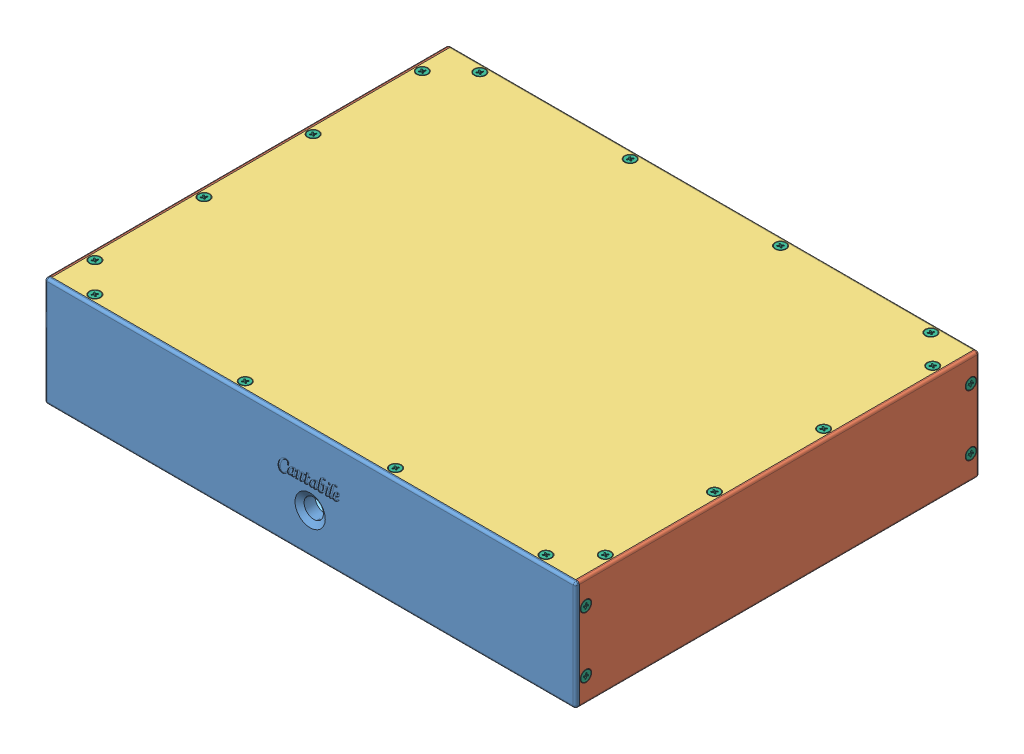
SolidWorks assembly 組合, configuration 預設. Lengths in mm.
Overall size (438 90 333).
46 component instances, 6 part files, 55 mates.
Components (placement in the parent):
- FrontPanel-2: FrontPanel [預設] at (-248.0238 109.7801 407.0399) size (438 90 12)
- SidePanel-3: SidePanel [預設] at (189.9762 199.7801 416.0399) x (0 0 -1) z (-1 0 0) size (330 90 12)
- SidePanel-4: SidePanel [預設] at (-248.0238 109.7801 416.0399) x (0 0 -1) z (1 0 0) size (330 90 12)
- top-1: top [預設] at (186.9762 195.7801 86.0399) x (-1 0 0) z (0 0 -1) size (432 4 330)
- BackPanel-2: BackPanel [預設] at (-236.0238 113.7801 86.0399) size (414 82 12)
- Bottom-1: Bottom [預設] at (186.9762 109.7801 86.0399) x (-1 0 0) z (0 0 -1) size (432 4 330)
- countersunk flat head cross recess screw_iso-1: countersunk flat head cross recess screw_iso [ISO 7046-1 - M4 x 8 - Z - 8C] at (-239.5238 199.7801 386.0399) x (0 -1 0) z (0.546944 0 -0.837169) size (8 8.4 8.4)
- countersunk flat head cross recess screw_iso-2: countersunk flat head cross recess screw_iso [ISO 7046-1 - M4 x 8 - Z - 8C] at (32.9762 199.7801 410.5399) x (0 -1 0) z (0.546944 0 -0.837169) size (8 8.4 8.4)
- countersunk flat head cross recess screw_iso-3: countersunk flat head cross recess screw_iso [ISO 7046-1 - M4 x 8 - Z - 8C] at (-215.0238 199.7801 410.5399) x (0 -1 0) z (0.546944 0 -0.837169) size (8 8.4 8.4)
- countersunk flat head cross recess screw_iso-4: countersunk flat head cross recess screw_iso [ISO 7046-1 - M4 x 8 - Z - 8C] at (-239.5238 199.7801 296.0399) x (0 -1 0) z (0.546944 0 -0.837169) size (8 8.4 8.4)
- countersunk flat head cross recess screw_iso-5: countersunk flat head cross recess screw_iso [ISO 7046-1 - M4 x 8 - Z - 8C] at (-215.0238 199.7801 93.0399) x (0 -1 0) z (0.546944 0 -0.837169) size (8 8.4 8.4)
- countersunk flat head cross recess screw_iso-6: countersunk flat head cross recess screw_iso [ISO 7046-1 - M4 x 8 - Z - 8C] at (-91.0238 199.7801 93.0399) x (0 -1 0) z (0.546944 0 -0.837169) size (8 8.4 8.4)
- countersunk flat head cross recess screw_iso-7: countersunk flat head cross recess screw_iso [ISO 7046-1 - M4 x 8 - Z - 8C] at (32.9762 199.7801 93.0399) x (0 -1 0) z (0.546944 0 -0.837169) size (8 8.4 8.4)
- countersunk flat head cross recess screw_iso-8: countersunk flat head cross recess screw_iso [ISO 7046-1 - M4 x 8 - Z - 8C] at (-91.0238 199.7801 410.5399) x (0 -1 0) z (0.546944 0 -0.837169) size (8 8.4 8.4)
- countersunk flat head cross recess screw_iso-9: countersunk flat head cross recess screw_iso [ISO 7046-1 - M4 x 8 - Z - 8C] at (-239.5238 199.7801 116.0399) x (0 -1 0) z (0.546944 0 -0.837169) size (8 8.4 8.4)
- countersunk flat head cross recess screw_iso-10: countersunk flat head cross recess screw_iso [ISO 7046-1 - M4 x 8 - Z - 8C] at (181.4762 199.7801 116.0399) x (0 -1 0) z (0.546944 0 -0.837169) size (8 8.4 8.4)
- countersunk flat head cross recess screw_iso-11: countersunk flat head cross recess screw_iso [ISO 7046-1 - M4 x 8 - Z - 8C] at (156.9762 199.7801 93.0399) x (0 -1 0) z (0.546944 0 -0.837169) size (8 8.4 8.4)
- countersunk flat head cross recess screw_iso-12: countersunk flat head cross recess screw_iso [ISO 7046-1 - M4 x 8 - Z - 8C] at (-248.0238 179.7801 410.5399) x (1 0 0) z (0 -0.564882 -0.825172) size (8 8.4 8.4)
- countersunk flat head cross recess screw_iso-13: countersunk flat head cross recess screw_iso [ISO 7046-1 - M4 x 8 - Z - 8C] at (-248.0238 179.7801 93.0399) x (1 0 0) z (0 -0.564882 -0.825172) size (8 8.4 8.4)
- countersunk flat head cross recess screw_iso-14: countersunk flat head cross recess screw_iso [ISO 7046-1 - M4 x 8 - Z - 8C] at (-248.0238 129.7801 410.5399) x (1 0 0) z (0 -0.564882 -0.825172) size (8 8.4 8.4)
- countersunk flat head cross recess screw_iso-15: countersunk flat head cross recess screw_iso [ISO 7046-1 - M4 x 8 - Z - 8C] at (181.4762 199.7801 296.0399) x (0 -1 0) z (0.546944 0 -0.837169) size (8 8.4 8.4)
- countersunk flat head cross recess screw_iso-16: countersunk flat head cross recess screw_iso [ISO 7046-1 - M4 x 8 - Z - 8C] at (181.4762 199.7801 206.0399) x (0 -1 0) z (0.546944 0 -0.837169) size (8 8.4 8.4)
- countersunk flat head cross recess screw_iso-17: countersunk flat head cross recess screw_iso [ISO 7046-1 - M4 x 8 - Z - 8C] at (156.9762 199.7801 410.5399) x (0 -1 0) z (0.546944 0 -0.837169) size (8 8.4 8.4)
- countersunk flat head cross recess screw_iso-18: countersunk flat head cross recess screw_iso [ISO 7046-1 - M4 x 8 - Z - 8C] at (181.4762 199.7801 386.0399) x (0 -1 0) z (0.546944 0 -0.837169) size (8 8.4 8.4)
- countersunk flat head cross recess screw_iso-19: countersunk flat head cross recess screw_iso [ISO 7046-1 - M4 x 8 - Z - 8C] at (-239.5238 199.7801 206.0399) x (0 -1 0) z (0.546944 0 -0.837169) size (8 8.4 8.4)
- countersunk flat head cross recess screw_iso-20: countersunk flat head cross recess screw_iso [ISO 7046-1 - M4 x 8 - Z - 8C] at (-91.0238 109.7801 93.0399) x (0 1 0) z (0 0 1) size (8 8.4 8.4)
- countersunk flat head cross recess screw_iso-21: countersunk flat head cross recess screw_iso [ISO 7046-1 - M4 x 8 - Z - 8C] at (-215.0238 109.7801 93.0399) x (0 1 0) z (0 0 1) size (8 8.4 8.4)
- countersunk flat head cross recess screw_iso-22: countersunk flat head cross recess screw_iso [ISO 7046-1 - M4 x 8 - Z - 8C] at (-239.5238 109.7801 116.0399) x (0 1 0) z (0 0 1) size (8 8.4 8.4)
- countersunk flat head cross recess screw_iso-26: countersunk flat head cross recess screw_iso [ISO 7046-1 - M4 x 8 - Z - 8C] at (-215.0238 109.7801 410.5399) x (0 1 0) z (0 0 -1) size (8 8.4 8.4)
- countersunk flat head cross recess screw_iso-27: countersunk flat head cross recess screw_iso [ISO 7046-1 - M4 x 8 - Z - 8C] at (-248.0238 129.7801 93.0399) x (1 0 0) z (0 -0.564882 -0.825172) size (8 8.4 8.4)
- countersunk flat head cross recess screw_iso-28: countersunk flat head cross recess screw_iso [ISO 7046-1 - M4 x 8 - Z - 8C] at (-239.5238 109.7801 296.0399) x (0 1 0) z (0 0 1) size (8 8.4 8.4)
- countersunk flat head cross recess screw_iso-29: countersunk flat head cross recess screw_iso [ISO 7046-1 - M4 x 8 - Z - 8C] at (-239.5238 109.7801 206.0399) x (0 1 0) z (0 0 1) size (8 8.4 8.4)
- countersunk flat head cross recess screw_iso-30: countersunk flat head cross recess screw_iso [ISO 7046-1 - M4 x 8 - Z - 8C] at (-91.0238 109.7801 410.5399) x (0 1 0) z (0 0 1) size (8 8.4 8.4)
- countersunk flat head cross recess screw_iso-31: countersunk flat head cross recess screw_iso [ISO 7046-1 - M4 x 8 - Z - 8C] at (-239.5238 109.7801 386.0399) x (0 1 0) z (0 0 1) size (8 8.4 8.4)
- countersunk flat head cross recess screw_iso-32: countersunk flat head cross recess screw_iso [ISO 7046-1 - M4 x 8 - Z - 8C] at (189.9762 129.7801 410.5399) x (-1 0 0) z (0 -0.982583 0.185827) size (8 8.4 8.4)
- countersunk flat head cross recess screw_iso-33: countersunk flat head cross recess screw_iso [ISO 7046-1 - M4 x 8 - Z - 8C] at (32.9762 109.7801 93.0399) x (0 1 0) z (0 0 1) size (8 8.4 8.4)
- countersunk flat head cross recess screw_iso-34: countersunk flat head cross recess screw_iso [ISO 7046-1 - M4 x 8 - Z - 8C] at (156.9762 109.7801 410.5399) x (0 1 0) z (0 0 1) size (8 8.4 8.4)
- countersunk flat head cross recess screw_iso-35: countersunk flat head cross recess screw_iso [ISO 7046-1 - M4 x 8 - Z - 8C] at (189.9762 179.7801 93.0399) x (-1 0 0) z (0 -0.982583 0.185827) size (8 8.4 8.4)
- countersunk flat head cross recess screw_iso-36: countersunk flat head cross recess screw_iso [ISO 7046-1 - M4 x 8 - Z - 8C] at (181.4762 109.7801 386.0399) x (0 1 0) z (0 0 1) size (8 8.4 8.4)
- countersunk flat head cross recess screw_iso-37: countersunk flat head cross recess screw_iso [ISO 7046-1 - M4 x 8 - Z - 8C] at (32.9762 109.7801 410.5399) x (0 1 0) z (0 0 1) size (8 8.4 8.4)
- countersunk flat head cross recess screw_iso-38: countersunk flat head cross recess screw_iso [ISO 7046-1 - M4 x 8 - Z - 8C] at (189.9762 129.7801 93.0399) x (-1 0 0) z (0 -0.982583 0.185827) size (8 8.4 8.4)
- countersunk flat head cross recess screw_iso-39: countersunk flat head cross recess screw_iso [ISO 7046-1 - M4 x 8 - Z - 8C] at (181.4762 109.7801 296.0399) x (0 1 0) z (0 0 1) size (8 8.4 8.4)
- countersunk flat head cross recess screw_iso-40: countersunk flat head cross recess screw_iso [ISO 7046-1 - M4 x 8 - Z - 8C] at (156.9762 109.7801 93.0399) x (0 1 0) z (0 0 1) size (8 8.4 8.4)
- countersunk flat head cross recess screw_iso-41: countersunk flat head cross recess screw_iso [ISO 7046-1 - M4 x 8 - Z - 8C] at (181.4762 109.7801 206.0399) x (0 1 0) z (0 0 1) size (8 8.4 8.4)
- countersunk flat head cross recess screw_iso-42: countersunk flat head cross recess screw_iso [ISO 7046-1 - M4 x 8 - Z - 8C] at (181.4762 109.7801 116.0399) x (0 1 0) z (0 0 1) size (8 8.4 8.4)
- countersunk flat head cross recess screw_iso-44: countersunk flat head cross recess screw_iso [ISO 7046-1 - M4 x 8 - Z - 8C] at (189.9762 179.7801 410.5399) x (-1 0 0) z (0 -0.982583 0.185827) size (8 8.4 8.4)
Mates (geometry in assembly coordinates):
- 重合/共線/共點1: coincident: plane of assembly; plane of assembly; plane of FrontPanel-2 through (-248.0238 199.7801 416.0399) normal (0 0 -1); plane of SidePanel-3 through (177.9762 199.7801 416.0399) normal (0 0 1)
- 重合/共線/共點2: coincident: line of assembly; line of assembly; line of FrontPanel-2 through (189.9762 197.7801 416.0399) axis (0 -1 0); line of SidePanel-3 through (189.9762 111.7801 416.0399) axis (0 1 0)
- 重合/共線/共點4: coincident: line of assembly; line of assembly; line of FrontPanel-2 through (-246.0238 199.7801 416.0399) axis (1 0 0); line of SidePanel-3 through (186.9762 199.7801 416.0399) axis (1 0 0)
- 重合/共線/共點6: coincident: plane of assembly; plane of assembly; plane of FrontPanel-2 through (-248.0238 199.7801 416.0399) normal (0 0 -1); plane of SidePanel-4 through (-236.0238 109.7801 416.0399) normal (0 0 1)
- 重合/共線/共點7: coincident: plane of assembly; plane of assembly; plane of FrontPanel-2 through (-236.0238 109.7801 407.0399) normal (-1 0 0); plane of SidePanel-4 through (-236.0238 109.7801 416.0399) normal (1 0 0)
- 重合/共線/共點8: coincident: line of assembly; line of assembly; line of FrontPanel-2 through (-236.0238 195.7801 416.0399) axis (0 0 -1); line of SidePanel-4 through (-236.0238 195.7801 86.0399) axis (0 0 1)
- 重合/共線/共點17: coincident: plane of assembly; plane of assembly; plane of FrontPanel-2 through (-248.0238 195.7801 407.0399) normal (0 1 0); plane of top-1 through (186.9762 195.7801 86.0399) normal (0 -1 0)
- 重合/共線/共點18: coincident: plane of assembly; plane of assembly; plane of SidePanel-4 through (-245.0238 199.7801 86.0399) normal (1 0 0); plane of top-1 through (-245.0238 199.7801 86.0399) normal (-1 0 0)
- 重合/共線/共點19: coincident: plane of assembly; plane of assembly; plane of FrontPanel-2 through (-248.0238 199.7801 416.0399) normal (0 0 -1); plane of top-1 through (186.9762 199.7801 416.0399) normal (0 0 1)
- 重合/共線/共點20: coincident: plane of assembly; plane of assembly; plane of top-1 through (186.9762 195.7801 86.0399) normal (0 -1 0); plane of BackPanel-2 through (-236.0238 195.7801 98.0399) normal (0 1 0)
- 重合/共線/共點21: coincident: line of assembly; line of assembly; line of top-1 through (186.9762 195.7801 86.0399) axis (-1 0 0); line of BackPanel-2 through (177.9762 195.7801 86.0399) axis (-1 0 0)
- 重合/共線/共點22: coincident: plane of assembly; plane of assembly; plane of SidePanel-4 through (-236.0238 109.7801 416.0399) normal (1 0 0); plane of BackPanel-2 through (-236.0238 113.7801 98.0399) normal (-1 0 0)
- 重合/共線/共點29: coincident: plane of assembly; plane of assembly; plane of BackPanel-2 through (-236.0238 113.7801 98.0399) normal (0 -1 0); plane of Bottom-1 through (186.9762 113.7801 86.0399) normal (0 1 0)
- 重合/共線/共點30: coincident: line of assembly; line of assembly; line of BackPanel-2 through (-236.0238 113.7801 86.0399) axis (1 0 0); line of Bottom-1 through (186.9762 113.7801 86.0399) axis (-1 0 0)
- 重合/共線/共點32: coincident: line of assembly; line of assembly; line of SidePanel-4 through (-245.0238 113.7801 86.0399) axis (0 0 1); line of Bottom-1 through (-245.0238 113.7801 86.0399) axis (0 0 1)
- 重合/共線/共點33: coincident: cone of assembly; cone of assembly; cone of top-1 through (-239.5238 199.7801 386.0399) axis (0 -1 0); cone of countersunk flat head cross recess screw_iso-1 through (-239.5238 199.2801 386.0399) axis (0 -1 0)
- 重合/共線/共點34: coincident: cone of assembly; cone of assembly; cone of top-1 through (-239.5238 199.7801 296.0399) axis (0 -1 0); cone of countersunk flat head cross recess screw_iso-4 through (-239.5238 199.2801 296.0399) axis (0 -1 0)
- 重合/共線/共點35: coincident: cone of assembly; cone of assembly; cone of top-1 through (32.9762 199.7801 410.5399) axis (0 -1 0); cone of countersunk flat head cross recess screw_iso-2 through (32.9762 199.2801 410.5399) axis (0 -1 0)
- 重合/共線/共點36: coincident: cone of assembly; cone of assembly; cone of top-1 through (181.4762 199.7801 386.0399) axis (0 -1 0); cone of countersunk flat head cross recess screw_iso-18 through (181.4762 199.2801 386.0399) axis (0 -1 0)
- 重合/共線/共點37: coincident: cone of assembly; cone of assembly; cone of top-1 through (156.9762 199.7801 410.5399) axis (0 -1 0); cone of countersunk flat head cross recess screw_iso-17 through (156.9762 199.2801 410.5399) axis (0 -1 0)
- 重合/共線/共點39: coincident: cone of assembly; cone of assembly; cone of top-1 through (-215.0238 199.7801 410.5399) axis (0 -1 0); cone of countersunk flat head cross recess screw_iso-3 through (-215.0238 199.2801 410.5399) axis (0 -1 0)
- 重合/共線/共點40: coincident: circle of assembly; cone of assembly; circle of top-1; cone of countersunk flat head cross recess screw_iso-8 through (-91.0238 199.2801 410.5399) axis (0 -1 0)
- 重合/共線/共點41: coincident: cone of assembly; cone of assembly; cone of top-1 through (-239.5238 199.7801 206.0399) axis (0 -1 0); cone of countersunk flat head cross recess screw_iso-19 through (-239.5238 199.2801 206.0399) axis (0 -1 0)
- 重合/共線/共點42: coincident: cone of assembly; cone of assembly; cone of top-1 through (-239.5238 199.7801 116.0399) axis (0 -1 0); cone of countersunk flat head cross recess screw_iso-9 through (-239.5238 199.2801 116.0399) axis (0 -1 0)
- 重合/共線/共點43: coincident: cone of assembly; cone of assembly; cone of top-1 through (-215.0238 199.7801 93.0399) axis (0 -1 0); cone of countersunk flat head cross recess screw_iso-5 through (-215.0238 199.2801 93.0399) axis (0 -1 0)
- 重合/共線/共點44: coincident: cone of assembly; cone of assembly; cone of top-1 through (-91.0238 199.7801 93.0399) axis (0 -1 0); cone of countersunk flat head cross recess screw_iso-6 through (-91.0238 199.2801 93.0399) axis (0 -1 0)
- 重合/共線/共點45: coincident: cone of assembly; cone of assembly; cone of top-1 through (32.9762 199.7801 93.0399) axis (0 -1 0); cone of countersunk flat head cross recess screw_iso-7 through (32.9762 199.2801 93.0399) axis (0 -1 0)
- 重合/共線/共點46: coincident: cone of assembly; cone of assembly; cone of top-1 through (181.4762 199.7801 296.0399) axis (0 -1 0); cone of countersunk flat head cross recess screw_iso-15 through (181.4762 199.2801 296.0399) axis (0 -1 0)
- 重合/共線/共點47: coincident: cone of assembly; cone of assembly; cone of top-1 through (181.4762 199.7801 206.0399) axis (0 -1 0); cone of countersunk flat head cross recess screw_iso-16 through (181.4762 199.2801 206.0399) axis (0 -1 0)
- 重合/共線/共點48: coincident: cone of assembly; cone of assembly; cone of top-1 through (181.4762 199.7801 116.0399) axis (0 -1 0); cone of countersunk flat head cross recess screw_iso-10 through (181.4762 199.2801 116.0399) axis (0 -1 0)
- 重合/共線/共點49: coincident: cone of assembly; cone of assembly; cone of top-1 through (156.9762 199.7801 93.0399) axis (0 -1 0); cone of countersunk flat head cross recess screw_iso-11 through (156.9762 199.2801 93.0399) axis (0 -1 0)
- 重合/共線/共點52: coincident: cone of assembly; cone of assembly; cone of SidePanel-4 through (-248.0238 129.7801 410.5399) axis (1 0 0); cone of countersunk flat head cross recess screw_iso-14 through (-247.5238 129.7801 410.5399) axis (1 0 0)
- 重合/共線/共點54: coincident: cone of assembly; cone of assembly; cone of SidePanel-4 through (-248.0238 179.7801 410.5399) axis (1 0 0); cone of countersunk flat head cross recess screw_iso-12 through (-247.5238 179.7801 410.5399) axis (1 0 0)
- 重合/共線/共點55: coincident: cone of assembly; cone of assembly; cone of SidePanel-4 through (-248.0238 179.7801 93.0399) axis (1 0 0); cone of countersunk flat head cross recess screw_iso-13 through (-247.5238 179.7801 93.0399) axis (1 0 0)
- 重合/共線/共點56: coincident: cone of assembly; cone of assembly; cone of SidePanel-4 through (-248.0238 129.7801 93.0399) axis (1 0 0); cone of countersunk flat head cross recess screw_iso-27 through (-247.5238 129.7801 93.0399) axis (1 0 0)
- 重合/共線/共點57: coincident: cone of assembly; cone of assembly; cone of Bottom-1 through (-239.5238 109.7801 386.0399) axis (0 1 0); cone of countersunk flat head cross recess screw_iso-31 through (-239.5238 110.2801 386.0399) axis (0 1 0)
- 重合/共線/共點58: coincident: circle of assembly; cone of assembly; circle of Bottom-1; cone of countersunk flat head cross recess screw_iso-26 through (-215.0238 110.2801 410.5399) axis (0 1 0)
- 重合/共線/共點59: coincident: cone of assembly; cone of assembly; cone of Bottom-1 through (-91.0238 109.7801 410.5399) axis (0 1 0); cone of countersunk flat head cross recess screw_iso-30 through (-91.0238 110.2801 410.5399) axis (0 1 0)
- 重合/共線/共點60: coincident: cone of assembly; cone of assembly; cone of Bottom-1 through (-239.5238 109.7801 296.0399) axis (0 1 0); cone of countersunk flat head cross recess screw_iso-28 through (-239.5238 110.2801 296.0399) axis (0 1 0)
- 重合/共線/共點61: coincident: cone of assembly; cone of assembly; cone of Bottom-1 through (-239.5238 109.7801 206.0399) axis (0 1 0); cone of countersunk flat head cross recess screw_iso-29 through (-239.5238 110.2801 206.0399) axis (0 1 0)
- 重合/共線/共點62: coincident: cone of assembly; cone of assembly; cone of Bottom-1 through (-91.0238 109.7801 93.0399) axis (0 1 0); cone of countersunk flat head cross recess screw_iso-20 through (-91.0238 110.2801 93.0399) axis (0 1 0)
- 重合/共線/共點63: coincident: cone of assembly; cone of assembly; cone of Bottom-1 through (-215.0238 109.7801 93.0399) axis (0 1 0); cone of countersunk flat head cross recess screw_iso-21 through (-215.0238 110.2801 93.0399) axis (0 1 0)
- 重合/共線/共點64: coincident: cone of assembly; cone of assembly; cone of Bottom-1 through (-239.5238 109.7801 116.0399) axis (0 1 0); cone of countersunk flat head cross recess screw_iso-22 through (-239.5238 110.2801 116.0399) axis (0 1 0)
- 重合/共線/共點65: coincident: cone of assembly; cone of assembly; cone of Bottom-1 through (32.9762 109.7801 93.0399) axis (0 1 0); cone of countersunk flat head cross recess screw_iso-33 through (32.9762 110.2801 93.0399) axis (0 1 0)
- 重合/共線/共點66: coincident: cone of assembly; cone of assembly; cone of Bottom-1 through (156.9762 109.7801 93.0399) axis (0 1 0); cone of countersunk flat head cross recess screw_iso-40 through (156.9762 110.2801 93.0399) axis (0 1 0)
- 重合/共線/共點67: coincident: cone of assembly; cone of assembly; cone of Bottom-1 through (181.4762 109.7801 116.0399) axis (0 1 0); cone of countersunk flat head cross recess screw_iso-42 through (181.4762 110.2801 116.0399) axis (0 1 0)
- 重合/共線/共點68: coincident: cone of assembly; cone of assembly; cone of Bottom-1 through (181.4762 109.7801 206.0399) axis (0 1 0); cone of countersunk flat head cross recess screw_iso-41 through (181.4762 110.2801 206.0399) axis (0 1 0)
- 重合/共線/共點69: coincident: cone of assembly; cone of assembly; cone of Bottom-1 through (181.4762 109.7801 296.0399) axis (0 1 0); cone of countersunk flat head cross recess screw_iso-39 through (181.4762 110.2801 296.0399) axis (0 1 0)
- 重合/共線/共點70: coincident: cone of assembly; cone of assembly; cone of Bottom-1 through (181.4762 109.7801 386.0399) axis (0 1 0); cone of countersunk flat head cross recess screw_iso-36 through (181.4762 110.2801 386.0399) axis (0 1 0)
- 重合/共線/共點71: coincident: cone of assembly; cone of assembly; cone of Bottom-1 through (32.9762 109.7801 410.5399) axis (0 1 0); cone of countersunk flat head cross recess screw_iso-37 through (32.9762 110.2801 410.5399) axis (0 1 0)
- 重合/共線/共點72: coincident: cone of assembly; cone of assembly; cone of Bottom-1 through (156.9762 109.7801 410.5399) axis (0 1 0); cone of countersunk flat head cross recess screw_iso-34 through (156.9762 110.2801 410.5399) axis (0 1 0)
- 重合/共線/共點73: coincident: cone of assembly; cone of assembly; cone of SidePanel-3 through (189.9762 129.7801 93.0399) axis (-1 0 0); cone of countersunk flat head cross recess screw_iso-38 through (189.4762 129.7801 93.0399) axis (-1 0 0)
- 重合/共線/共點74: coincident: cone of assembly; cone of assembly; cone of SidePanel-3 through (189.9762 179.7801 93.0399) axis (-1 0 0); cone of countersunk flat head cross recess screw_iso-35 through (189.4762 179.7801 93.0399) axis (-1 0 0)
- 重合/共線/共點75: coincident: cone of assembly; cone of assembly; cone of SidePanel-3 through (189.9762 179.7801 410.5399) axis (-1 0 0); cone of countersunk flat head cross recess screw_iso-44 through (189.4762 179.7801 410.5399) axis (-1 0 0)
- 重合/共線/共點76: coincident: cone of assembly; cone of assembly; cone of SidePanel-3 through (189.9762 129.7801 410.5399) axis (-1 0 0); cone of countersunk flat head cross recess screw_iso-32 through (189.4762 129.7801 410.5399) axis (-1 0 0)
